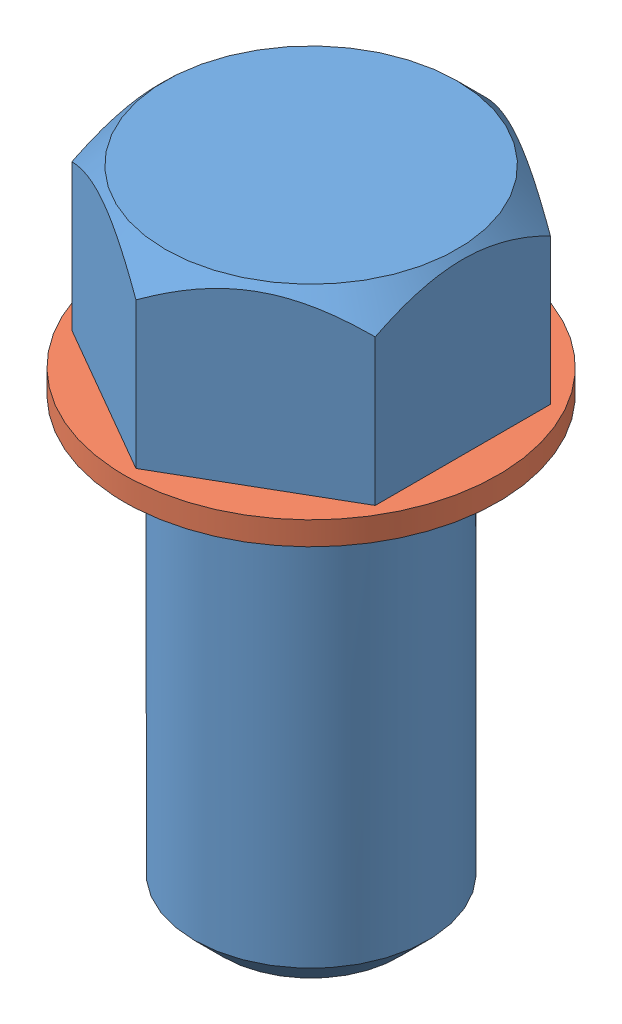
SolidWorks assembly Assem2, configuration Default. Lengths in mm.
Overall size (20.32 34.92 20.32).
2 component instances, 2 part files, 1 mates.
Components (placement in the parent):
- Bolt-1: Bolt [.5 bolt] at origin size (16.5 34.92 19.05)
- Washer-1: Washer [.5 washer] at (0 24.13 0) size (20.32 1.27 20.32)
Mates (geometry in assembly coordinates):
- ProfileCenter1: profile center anti-aligned: circle of Bolt-1; circle of Washer-1
